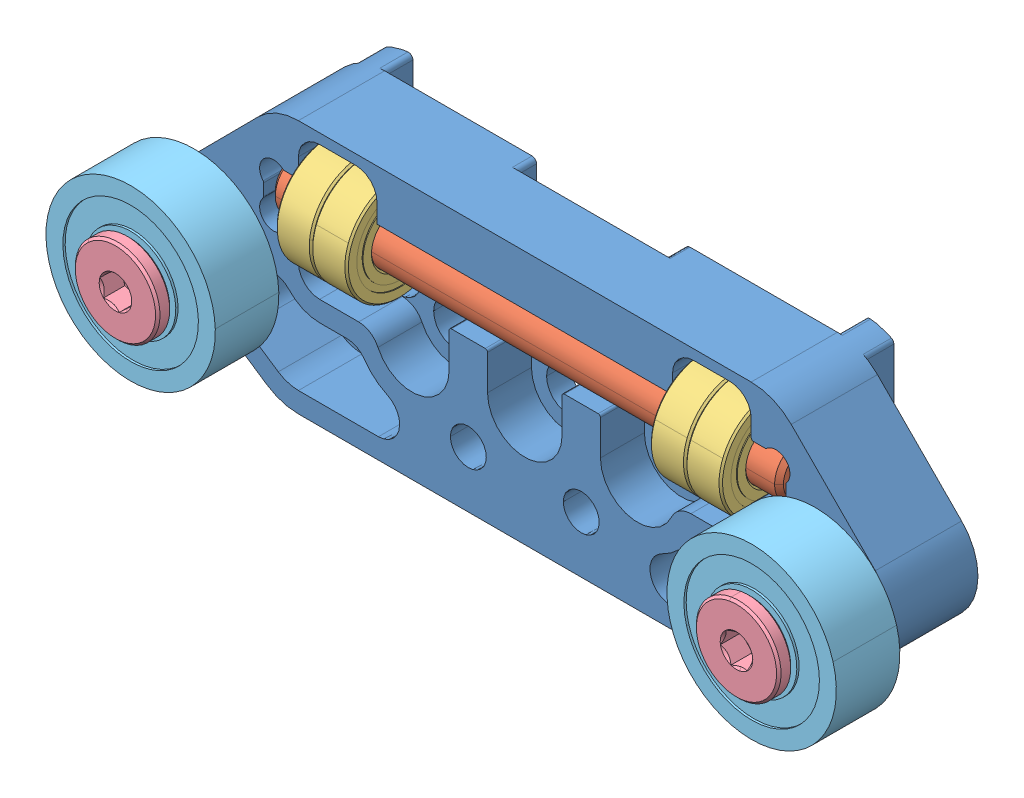
SolidWorks assembly WCP-0897-inline-clamping-bearing-block, configuration Default. Lengths in mm.
Overall size (91.46 28.57 24).
11 component instances, 5 part files, 0 mates.
Components (placement in the parent):
- WCP-0897^WCP-0897-inline-clamping-bearing-block-1: WCP-0897^WCP-0897-inline-clamping-bearing-block [Default] at origin size (91.46 28.57 24) (virtual)
  - WCP-0897-001 Rev1^WCP-0897_WCP-0897-inline-clamping-bearing-block-1: WCP-0897-001 Rev1^WCP-0897_WCP-0897-inline-clamping-bearing-block [Default] at origin size (82.55 28.57 15.14) (virtual)
  - WCP-0897-002 Rev1^WCP-0897_WCP-0897-inline-clamping-bearing-block-1: WCP-0897-002 Rev1^WCP-0897_WCP-0897-inline-clamping-bearing-block [Default] at (0 7.2009 6.7) size (57.15 5.97 5.97) (virtual)
  - WCP-0498 Rev1^WCP-0897_WCP-0897-inline-clamping-bearing-block-1: WCP-0498 Rev1^WCP-0897_WCP-0897-inline-clamping-bearing-block [Default] at (-23.0439 7.2009 6.7) x (0 0.994493 -0.104801) z (1 0 0) size (12 12 4) (virtual)
  - WCP-0498 Rev1^WCP-0897_WCP-0897-inline-clamping-bearing-block-2: WCP-0498 Rev1^WCP-0897_WCP-0897-inline-clamping-bearing-block [Default] at (-19.0439 7.2009 6.7) x (0 -0.358315 -0.933601) z (1 0 0) size (12 12 4) (virtual)
  - WCP-0498 Rev1^WCP-0897_WCP-0897-inline-clamping-bearing-block-3: WCP-0498 Rev1^WCP-0897_WCP-0897-inline-clamping-bearing-block [Default] at (19.0439 7.2009 6.7) x (0 -0.367996 -0.929827) z (1 0 0) size (12 12 4) (virtual)
  - WCP-0498 Rev1^WCP-0897_WCP-0897-inline-clamping-bearing-block-4: WCP-0498 Rev1^WCP-0897_WCP-0897-inline-clamping-bearing-block [Default] at (23.0439 7.2009 6.7) x (0 -0.367996 -0.929827) z (1 0 0) size (12 12 4) (virtual)
  - WCP-0473 Rev1^WCP-0897_WCP-0897-inline-clamping-bearing-block-1: WCP-0473 Rev1^WCP-0897_WCP-0897-inline-clamping-bearing-block [Default] at (-34.925 0 10.4966) x (0.732794 0.68045 0) z (0.68045 -0.732794 0) size (9.53 20.65 9.53) (virtual)
  - WCP-0473 Rev1^WCP-0897_WCP-0897-inline-clamping-bearing-block-2: WCP-0473 Rev1^WCP-0897_WCP-0897-inline-clamping-bearing-block [Default] at (34.925 0 10.4966) x (0.98463 0.174654 0) z (0.174654 -0.98463 0) size (9.53 20.65 9.53) (virtual)
  - WCP-0212_0_250_radial_bearing^WCP-0897_WCP-0897-inline-clamping-bearing-block-1: WCP-0212_0_250_radial_bearing^WCP-0897_WCP-0897-inline-clamping-bearing-block [Default] at (-34.925 0 15.5353) x (0.999468 0.032626 0) z (0 0 1) size (19.05 19.05 7.14) (virtual)
  - WCP-0212_0_250_radial_bearing^WCP-0897_WCP-0897-inline-clamping-bearing-block-2: WCP-0212_0_250_radial_bearing^WCP-0897_WCP-0897-inline-clamping-bearing-block [Default] at (34.925 0 15.5353) x (0.961226 0.27576 0) z (0 0 1) size (19.05 19.05 7.14) (virtual)
